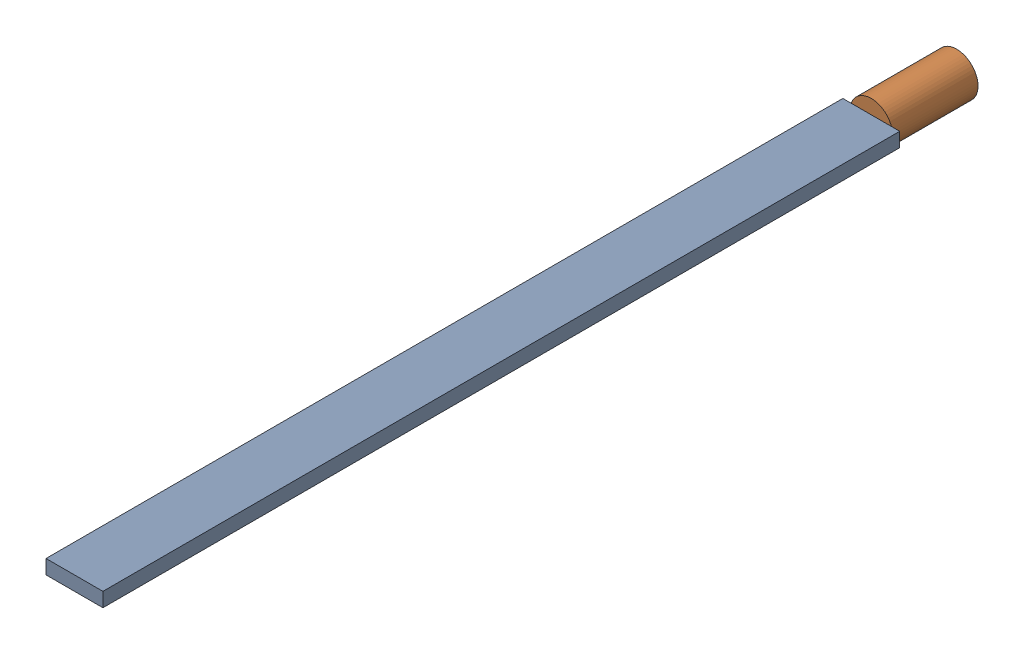
SolidWorks assembly 01-094-00-0, configuration Default. Lengths in mm.
Overall size (26.02 26.02 393.7).
2 component instances, 2 part files, 0 mates.
Components (placement in the parent):
- 01-093-00-0-1: 01-093-00-0 [Default] at (-45.5164 -22.3944 39.2328) size (25.4 6.35 355.6)
- TROD 0.7500-1x1.25-1: TROD 0.7500-1x1.25 [Default] at (-32.8164 -19.2194 -316.3672) x (0.5 -0.866025 0) z (0.866025 0.5 0) size (19.05 38.1 19.05)
